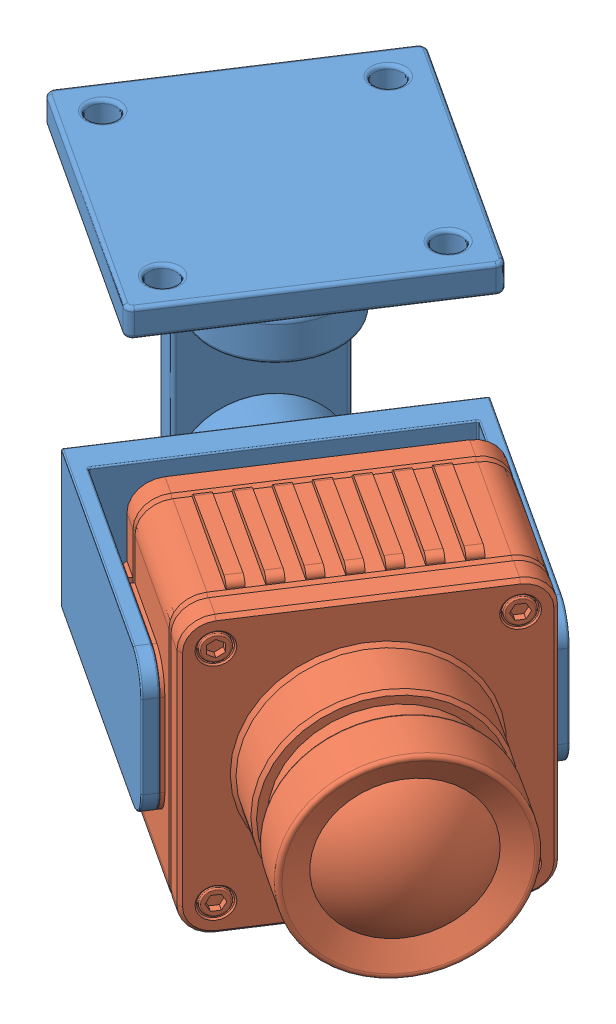
SolidWorks assembly camera gimbal assembly, configuration Default. Lengths in mm.
Overall size (48.97 31.09 42.31).
2 component instances, 2 part files, 4 mates.
Components (placement in the parent):
- Camera gimball-1: Camera gimball [Default] at (0 -15.5 -15.5) x (-0.837169 0 -0.546944) z (0 -1 0) size (30 22.5 25.5)
- camera DJI FPV-1: camera DJI FPV [Default] at (12.3482 -20.5 -7.4326) x (0.546944 0 -0.837169) z (0.837169 0 0.546944) size (20.5 21.17 32.8)
Mates (geometry in assembly coordinates):
- Concentric2: concentric aligned: cylinder of Camera gimball-1 through (17.907 -23.5 -13.6555) axis (0.546944 0 -0.837169) radius 1; cylinder of camera DJI FPV-1 through (17.7703 -23.5 -13.4462) axis (0.546944 0 -0.837169) radius 1
- Concentric3: concentric aligned: cylinder of Camera gimball-1 through (17.907 -17.5 -13.6555) axis (0.546944 0 -0.837169) radius 1; cylinder of camera DJI FPV-1 through (17.7703 -17.5 -13.4462) axis (0.546944 0 -0.837169) radius 1
- Coincident1: coincident anti-aligned: plane of Camera gimball-1 through (5.6062 -25.5 -24.081) normal (-0.546944 0 0.837169); plane of camera DJI FPV-1 through (19.0009 -23.5 -15.3299) normal (0.546944 0 -0.837169)
- Coincident2: coincident aligned: plane of Camera gimball-1 through (0 0 -15.5) normal (0 1 0); plane of assembly through (0 0 0) normal (0 1 0)
